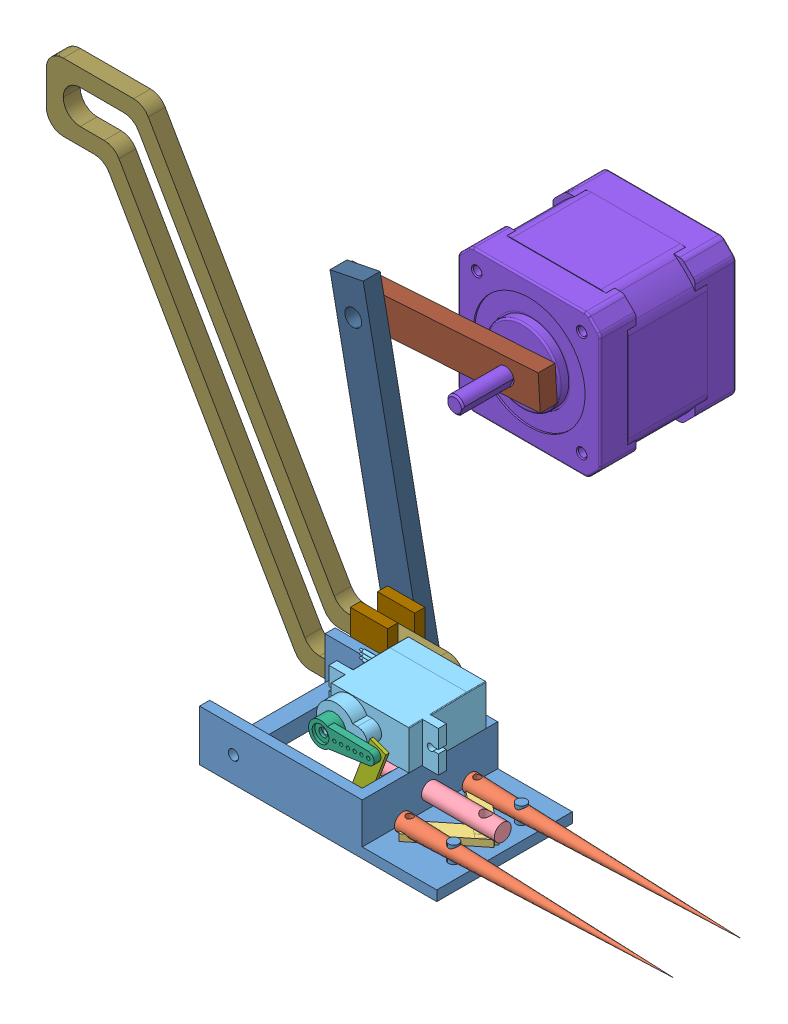
SolidWorks assembly gripper_asm, configuration Default. Lengths in mm.
Overall size (218.24 125 103).
15 component instances, 12 part files, 31 mates.
Components (placement in the parent):
- gripper_arm_mount-1: gripper_arm_mount [Default] at (-32.466 -3.7192 32.867) size (70 15 40)
- gripper_arm-1: gripper_arm [Default] at (-27.466 1.7808 62.867) x (0 0 1) z (-1 0 0) size (5 5.06 80)
- gripper_arm-2: gripper_arm [Default] at (-27.466 1.7808 42.867) x (0 0 1) z (-1 0 0) size (5 5.06 80)
- rod1-1: rod1 [Default] at (-19.221 1.2808 57.867) x (-0.780625 0 0.625) z (0 -1 0) size (20 5 2)
- rod1-2: rod1 [Default] at (-19.221 1.2808 47.867) x (-0.780625 0 -0.625) z (0 -1 0) size (20 5 2)
- rod2-1: rod2 [Default] at (-7.976 3.7808 52.867) x (0 1 0) z (0 0 1) size (5 35 17.5)
- Tower Pro 9g Micro Servo SG90-4: Tower Pro 9g Micro Servo SG90 [Default] at (-45.366 16.9858 52.707) x (1 0 0) z (0 -1 0) size (36.67 31.5 22.48) (flexible)
  - Tower Pro 9g Micro Servo SG90-1: Tower Pro 9g Micro Servo SG90 [Default] at origin size (36.67 29.95 12.59)
  - SG90 plastic Horn-1: SG90 plastic Horn [Default] at (-1.405 13.16 0) x (0.998217 0 -0.059686) z (0.059686 0 0.998217) size (19.4 4 7.07)
- linear_link-1: linear_link [Default] at (-35.3435 10.8037 64.867) x (0.350993 0.936378 0) z (0.936378 -0.350993 0) size (20 1 5)
- nema  17-1: nema  17 [По умолчанию] at (-43.2016 84.7808 -30.133) x (1 0 0) z (0 -1 0) size (42.3 62 51.35)
- guide_slider-1: guide_slider [Default] at (-71.966 3.7808 27.367) x (0 0 -1) z (1 0 0) size (11 30 11)
- path_link2-1: path_link2 [Default] at (-75.2932 43.0075 16.867) x (-0.195681 0.980668 0) z (0 0 1) size (100 10 5)
- path_link1-2: path_link1 [Default] at (-63.161 83.5075 11.867) x (-0.997971 -0.063665 0) z (0 0 1) size (60 10 5)
- travel_path-2: travel_path [Default] at (-82.2016 8.7808 24.867) size (118.51 120 5)
Mates (geometry in assembly coordinates):
- Concentric2: concentric anti-aligned: cylinder of gripper_arm_mount-1 through (-12.466 4.2808 62.867) axis (0 -1 0) radius 1.5; cylinder of gripper_arm-1 through (-12.466 -0.7192 62.867) axis (0 1 0) radius 1.5
- Concentric3: concentric anti-aligned: cylinder of gripper_arm_mount-1 through (-12.466 4.2808 42.867) axis (0 -1 0) radius 1.5; cylinder of gripper_arm-2 through (-12.466 -0.7192 42.867) axis (0 1 0) radius 1.5
- Tangent3: tangent: plane of gripper_arm_mount-1 through (-7.466 -0.7192 72.867) normal (0 1 0); circle of gripper_arm-2
- Tangent4: tangent: plane of gripper_arm_mount-1 through (-7.466 -0.7192 72.867) normal (0 1 0); circle of gripper_arm-1
- Concentric5: concentric aligned: cylinder of gripper_arm-1 through (-25.466 -0.7192 62.867) axis (0 1 0) radius 1; cylinder of rod-1 through (-25.466 -0.7192 62.867) axis (0 1 0) radius 1
- Coincident5: coincident anti-aligned: plane of gripper_arm_mount-1 through (-7.466 -0.7192 72.867) normal (0 1 0); plane of rod-1 through (-19.221 -0.7192 57.867) normal (0 -1 0)
- Concentric6: concentric aligned: cylinder of gripper_arm-2 through (-25.466 -0.7192 42.867) axis (0 1 0) radius 1; cylinder of rod-2 through (-25.466 -0.7192 42.867) axis (0 1 0) radius 1
- Coincident7: coincident anti-aligned: plane of gripper_arm_mount-1 through (-7.466 -0.7192 72.867) normal (0 1 0); plane of rod-2 through (-19.221 -0.7192 47.867) normal (0 -1 0)
- Concentric7: concentric aligned: cylinder of rod-1 through (-12.976 -0.7192 52.867) axis (0 1 0) radius 1; cylinder of rod-2 through (-12.976 -0.7192 52.867) axis (0 1 0) radius 1
- Concentric8: concentric aligned: cylinder of rod-2 through (-12.976 -0.7192 52.867) axis (0 1 0) radius 1; cylinder of rod2-1 through (-12.976 1.2808 52.867) axis (0 1 0) radius 1.5
- Concentric9: concentric anti-aligned: cylinder of gripper_arm_mount-1 through (-7.466 3.7808 52.867) axis (-1 0 0) radius 2.5; cylinder of rod2-1 through (-42.976 3.7808 52.867) axis (1 0 0) radius 2.5
- Concentric15: concentric aligned: cylinder of rod2-1 through (-37.976 3.7808 67.867) axis (0 0 -1) radius 1.5; cylinder of linear_link-1 through (-37.976 3.7808 65.867) axis (0 0 -1) radius 1.25
- Concentric16: concentric aligned: cylinder of Tower Pro 9g Micro Servo SG90-4/SG90 plastic Horn-1 through (-32.7111 17.8265 81.8208) axis (0 0 -1) radius 0.5; cylinder of linear_link-1 through (-32.7111 17.8265 65.867) axis (0 0 -1) radius 1.25
- Distance2: distance = 12 mm aligned: plane of gripper_arm_mount-1 through (-29.466 11.2808 72.867) normal (0 1 0); plane of Tower Pro 9g Micro Servo SG90-4/Tower Pro 9g Micro Servo SG90-1 through (-45.366 23.2808 52.707) normal (0 1 0)
- Coincident29: coincident aligned: plane of gripper_arm_mount-1 through (-29.466 -0.7192 72.867) normal (1 0 0); plane of Tower Pro 9g Micro Servo SG90-4/Tower Pro 9g Micro Servo SG90-1 through (-29.466 10.6908 52.707) normal (1 0 0)
- Distance5: distance = 5 mm aligned: plane of Tower Pro 9g Micro Servo SG90-4/SG90 plastic Horn-1 through (-43.2423 17.1968 67.867) normal (0 0 1); plane of gripper_arm_mount-1 through (-32.466 -3.7192 72.867) normal (0 0 1)
- Coincident38: coincident: plane of Tower Pro 9g Micro Servo SG90-4/SG90 plastic Horn-1 through (-46.771 16.9858 65.867) normal (0 0 -1); line of linear_link-1 through (-36.5125 0.5624 65.867) axis (0.350993 0.936378 0)
- Coincident43: coincident anti-aligned: plane of gripper_arm_mount-1 through (-69.966 6.2808 76.938) normal (0 1 0); plane of guide_slider-1 through (-64.966 6.2808 32.867) normal (0 -1 0)
- Coincident44: coincident anti-aligned: plane of gripper_arm_mount-1 through (-69.966 6.2808 76.938) normal (-1 0 0); plane of guide_slider-1 through (-69.966 6.2808 32.867) normal (1 0 0)
- Concentric19: concentric aligned: cylinder of nema  17-1 through (-43.2016 84.7808 31.867) axis (0 0 -1) radius 2.5; cylinder of path_link1-2 through (-43.2016 84.7808 16.867) axis (0 0 -1) radius 2.5
- Concentric20: concentric aligned: cylinder of path_link2-1 through (-83.1204 82.2342 21.867) axis (0 0 -1) radius 2.5; cylinder of path_link1-2 through (-83.1204 82.2342 16.867) axis (0 0 -1) radius 2.5
- Coincident52: coincident anti-aligned: plane of path_link2-1 through (-75.2932 43.0075 16.867) normal (0 0 -1); plane of path_link1-2 through (-63.161 83.5075 16.867) normal (0 0 1)
- Coincident53: coincident anti-aligned: plane of nema  17-1 through (-43.2016 84.7808 11.867) normal (0 0 1); plane of path_link1-2 through (-63.161 83.5075 11.867) normal (0 0 -1)
- Parallel3: parallel anti-aligned: plane of gripper_arm_mount-1 through (-29.466 -0.7192 72.867) normal (1 0 0); plane of gripper_arm-1 through (-27.466 1.7808 62.867) normal (-1 0 0)
- Concentric21: concentric anti-aligned: cylinder of gripper_arm_mount-1 through (-67.466 3.7808 32.867) axis (0 0 1) radius 1.5; cylinder of path_link2-1 through (-67.466 3.7808 21.867) axis (0 0 -1) radius 2.5
- Coincident61: coincident anti-aligned: plane of guide_slider-1 through (-72.966 18.7808 21.867) normal (0 0 -1); plane of path_link2-1 through (-75.2932 43.0075 21.867) normal (0 0 1)
- Coincident62: coincident anti-aligned: plane of guide_slider-1 through (-72.966 8.7808 29.867) normal (0 0 -1); plane of travel_path-2 through (-82.2016 8.7808 29.867) normal (0 0 1)
- Coincident67: coincident anti-aligned: plane of guide_slider-1 through (-72.966 8.7808 29.867) normal (0 1 0); plane of travel_path-2 through (-82.2016 8.7808 29.867) normal (0 -1 0)
- Distance7: distance = 25 mm aligned: plane of travel_path-2 through (-47.2016 13.7808 29.867) normal (1 0 0); plane of nema  17-1 through (-22.2016 84.7808 9.867) normal (1 0 0)
- Coincident70: coincident anti-aligned: plane of gripper_arm_mount-1 through (-32.466 -3.7192 32.867) normal (0 0 -1); plane of guide_slider-1 through (-72.966 18.7808 32.867) normal (0 0 1)
- Distance8: distance = 50 mm anti-aligned: plane of nema  17-1 through (-43.2016 63.7808 9.867) normal (0 -1 0); plane of travel_path-2 through (-79.3148 13.7808 29.867) normal (0 1 0)
